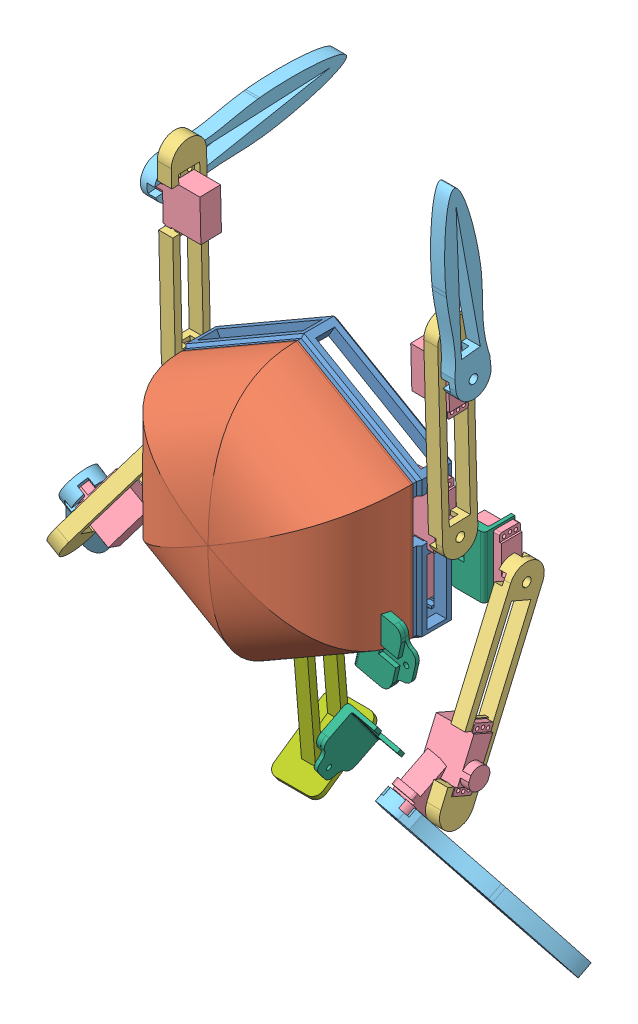
SolidWorks assembly robot, configuration Défaut. Lengths in mm.
Overall size (313.2 378.09 164.08).
31 component instances, 7 part files, 53 mates.
Components (placement in the parent):
- DAT PIECE-1: DAT PIECE [Défaut] at (-10.8836 70.1745 0) size (134 146.8 22)
- coque-1: coque [Défaut] at (-123.3481 -61.863 48.1765) x (0.5 0.866025 0) z (0 0 1) size (135.25 154.89 56.25)
- testBras-1: testBras [Défaut] at (78.5087 -93.5274 11.0123) x (0 -0.918186 0.39615) z (-1 0 0) size (120 20 26.15)
  - bras-1: bras [Défaut] at (-74.5383 -8.1052 -2) size (120 20 8)
  - servo-1: servo [Défaut] at (-8.5231 -3.9052 -3.5325) x (0 0 1) z (0 1 0) size (26.15 32.39 11.68)
- testBras-2: testBras [Défaut] at (-114.0009 -54.5505 25.2701) x (-0.418153 -0.72841 0.54274) z (0.867258 -0.49786 0) size (120 20 26.15)
  - bras-1: bras [Défaut] at (-74.5383 -8.1052 -2) size (120 20 8)
  - servo-1: servo [Défaut] at (-8.5231 -3.9052 -3.5325) x (0 0 1) z (0 1 0) size (26.15 32.39 11.68)
- pied-2: pied [Défaut] at (-131.5029 -60.6202 37.1735) x (-0.425802 -0.741735 -0.51819) z (0.867258 -0.49786 0) size (110.07 20 8)
- testBras-3: testBras [Défaut] at (-88.8405 91.642 9.4129) x (0 0.999727 0.023379) z (1 0 0) size (120 20 26.15)
  - bras-1: bras [Défaut] at (-74.5383 -8.1052 -2) size (120 20 8)
  - servo-1: servo [Défaut] at (-8.5231 -3.9052 -3.5325) x (0 0 1) z (0 1 0) size (26.15 32.39 11.68)
- testBras-4: testBras [Défaut] at (67.0733 79.8272 13.531) x (0 0.999613 0.027801) z (-1 0 0) size (120 20 26.15)
  - bras-1: bras [Défaut] at (-74.5383 -8.1052 -2) size (120 20 8)
  - servo-1: servo [Défaut] at (-8.5231 -3.9052 -3.5325) x (0 0 1) z (0 1 0) size (26.15 32.39 11.68)
- pied-4: pied [Défaut] at (78.8301 87.9868 21.7678) x (0 0.99396 0.109744) z (-1 0 0) size (110.07 20 8)
- servo-10: servo [Défaut] at (48.9164 -36.2368 -3.2325) x (0 0 1) z (-1 0 0) size (26.15 32.39 11.68)
- servo-11: servo [Défaut] at (-58.9996 -36.2368 -3.2325) x (0 0 1) z (-1 0 0) size (26.15 32.39 11.68)
- servo-12: servo [Défaut] at (60.6489 23.0996 3.7) x (-1 0 0) z (0 0 1) size (26.15 32.39 11.68)
- servo-13: servo [Défaut] at (-82.4161 -0.6494 3.7) size (26.15 32.39 11.68)
- servo-14: servo [Défaut] at (-7.6601 -44.5704 8.316) size (26.15 32.39 11.68)
- pantiltDD-1: pantiltDD [Défaut] at (53.2417 -26.5493 20.7075) x (0 0 1) z (0.97536 -0.220619 0) size (17.5 35 28.97)
- pantiltDD-2: pantiltDD [Défaut] at (-72.2366 -7.8234 20.7075) x (0 0 1) z (-0.867258 0.49786 0) size (17.5 35 28.97)
- pantiltDD-3: pantiltDD [Défaut] at (26.3946 -111.469 22.237) x (-0.97536 0.220619 0) z (-0.135924 -0.600921 0.787666) size (17.5 35 28.97)
- servo-15: servo [Défaut] at (-86.5996 -19.7221 -22.6409) x (0.867258 -0.49786 0) z (0 0 1) size (26.15 32.39 11.68)
- servo-16: servo [Défaut] at (72.0843 -6.6076 -22.6409) x (-1 0 0) z (0 0 1) size (26.15 32.39 11.68)
- pied-5: pied [Défaut] at (70.1824 -115.1027 46.0099) x (0.677703 -0.636329 -0.368516) z (0.135924 0.600921 -0.787666) size (110.07 20 8)
- servo-17: servo [Défaut] at (55.2998 -127.2042 23.5139) x (0.135924 0.600921 -0.787666) z (0.97536 -0.220619 0) size (26.15 32.39 11.68)
- pied-6: pied [Défaut] at (-100.7974 90.87 10.4039) x (0 0.118313 -0.992976) z (1 0 0) size (110.07 20 8)
- patteArriere-1: patteArriere [Défaut] at (-16.0845 -27.654 24.1475) x (0 -0.996691 -0.081285) z (1 0 0) size (135 38.82 28)
- pantiltDD-4: pantiltDD [Défaut] at (58.5518 -36.0076 -22.9569) x (0 0 1) z (-1 0 0) size (17.5 35 28.97)
Mates (geometry in assembly coordinates):
- Coaxiale7: concentric aligned: circle of testBras-2/servo-1; circle of pied-2
- Distance8: distance = 0.2 mm anti-aligned: plane of pied-2 through (-125.7142 -57.9683 28.6209) normal (0.867258 -0.49786 0); plane of testBras-2/servo-1 through (-125.5408 -58.0678 28.6209) normal (-0.867258 0.49786 0)
- Coaxiale9: concentric aligned: circle of ?; circle of testBras-4/bras-1
- Distance10: distance = 0.2 mm anti-aligned: plane of testBras-4/bras-1 through (74.1733 117.9458 9.5194) normal (-1 0 0); plane of ? through (74.3733 117.9458 9.5194) normal (1 0 0)
- Coaxiale11: concentric aligned: circle of testBras-4/servo-1; circle of pied-4
- Distance12: distance = 0.2 mm anti-aligned: plane of pied-4 through (75.1301 89.0842 11.8282) normal (-1 0 0); plane of testBras-4/servo-1 through (75.3301 89.0842 11.8282) normal (1 0 0)
- Distance17: distance = 0.2 mm anti-aligned: plane of servo-10 through (48.9164 -8.1698 1.3) normal (0 0 1); plane of DAT PIECE-1 through (19.1164 -41.8314 1.5) normal (0 0 -1)
- Coïncidente8: coincident anti-aligned: plane of DAT PIECE-1 through (56.1164 31.4921 20) normal (1 0 0); plane of servo-12 through (56.1164 -4.9674 3.7) normal (-1 0 0)
- Distance20: distance = 0.2 mm anti-aligned: plane of servo-12 through (60.6489 -0.6494 3.7) normal (0 0 -1); plane of DAT PIECE-1 through (56.1164 23.4506 3.5) normal (0 0 1)
- Distance21: distance = 0.4 mm anti-aligned: plane of servo-13 through (-82.4161 -0.6494 15.384) normal (0 -1 0); plane of DAT PIECE-1 through (56.1164 -1.0494 3.5) normal (0 1 0)
- Coïncidente11: coincident anti-aligned: plane of DAT PIECE-1 through (-77.8836 31.4921 20) normal (-1 0 0); plane of servo-13 through (-77.8836 27.4176 3.7) normal (1 0 0)
- Distance22: distance = 0.2 mm anti-aligned: plane of servo-13 through (-82.4161 23.0996 3.7) normal (0 0 -1); plane of DAT PIECE-1 through (56.1164 23.4506 3.5) normal (0 0 1)
- Distance23: distance = 0.4 mm anti-aligned: plane of servo-12 through (60.6489 -0.6494 15.384) normal (0 -1 0); plane of DAT PIECE-1 through (56.1164 -1.0494 3.5) normal (0 1 0)
- Coïncidente20: coincident: point of DAT PIECE-1; point of coque-1
- Coïncidente22: coincident anti-aligned: plane of DAT PIECE-1 through (54.6164 -45.0069 22) normal (0 0 1); plane of coque-1 through (-76.3836 30.626 22) normal (0 0 -1)
- Coïncidente23: coincident: plane of servo-11 through (-64.8642 -18.5076 -7.9569) normal (0 0 -1); plane of pantiltDD-2 through (-58.7534 -1.837 -7.9569) normal (0 0 1)
- Coaxiale13: concentric: circle of servo-11; circle of pantiltDD-2
- Coaxiale14: concentric: circle of servo-10; circle of pantiltDD-1
- Coïncidente24: coincident: plane of servo-10 through (43.0518 -18.5076 -7.9569) normal (0 0 -1); plane of pantiltDD-1 through (42.117 -36.2382 -7.9569) normal (0 0 1)
- Coïncidente25: coincident: plane of pantiltDD-2 through (-85.4695 -26.8574 -22.6409) normal (-0.867258 0.49786 0); plane of servo-15 through (-68.6953 2.3626 -22.6409) normal (0.867258 -0.49786 0)
- Coaxiale15: concentric: circle of pantiltDD-2; circle of servo-15
- Coïncidente27: coincident anti-aligned: plane of testBras-2/bras-1 through (-81.8702 -1.9943 -16.7763) normal (0.867258 -0.49786 0); plane of servo-15 through (-81.8702 -1.9943 -16.7763) normal (-0.867258 0.49786 0)
- Coaxiale16: concentric aligned: circle of testBras-2/bras-1; circle of servo-15
- Coaxiale17: concentric: circle of testBras-1/servo-1; circle of pantiltDD-3
- Coïncidente28: coincident: plane of testBras-1/servo-1; plane of pantiltDD-3 through (53.4684 -121.7028 8.0396) normal (-0.97536 0.220619 0)
- Coïncidente29: coincident: plane of pantiltDD-1 through (60.2877 -4.4641 -22.6409) normal (0.97536 -0.220619 0); plane of servo-16
- Coaxiale18: concentric: circle of pantiltDD-1; circle of servo-16
- Coïncidente30: coincident anti-aligned: plane of testBras-1/bras-1 through (76.8087 -24.3368 -16.7763) normal (-1 0 0); plane of servo-16 through (76.8087 -24.3368 -16.7763) normal (1 0 0)
- Coaxiale19: concentric aligned: circle of testBras-1/bras-1; circle of servo-16
- Coaxiale20: concentric: circle of pantiltDD-1; circle of servo-16
- Coaxiale21: concentric: circle of pantiltDD-2; circle of servo-15
- Coïncidente31: coincident: plane of pantiltDD-3 through (72.4165 -104.491 38.0415) normal (-0.135924 -0.600921 0.787666); plane of servo-17 through (60.7932 -102.9178 37.2359) normal (0.135924 0.600921 -0.787666)
- Coaxiale23: concentric: circle of pantiltDD-3; circle of servo-17
- Coaxiale24: concentric: circle of pantiltDD-3; circle of servo-17
- Coaxiale25: concentric aligned: circle of pied-5; circle of servo-17
- Coïncidente32: coincident anti-aligned: plane of pied-5 through (63.4586 -117.7164 38.1581) normal (0.135924 0.600921 -0.787666); plane of servo-17 through (63.4586 -117.7164 38.1581) normal (-0.135924 -0.600921 0.787666)
- Coaxiale26: concentric aligned: circle of testBras-3/servo-1; circle of pied-6
- Coïncidente33: coincident anti-aligned: plane of testBras-3/servo-1 through (-97.0974 100.7998 11.5871) normal (-1 0 0); plane of pied-6 through (-97.0974 100.7998 11.5871) normal (1 0 0)
- Coïncidente34: coincident anti-aligned: plane of testBras-3/bras-1 through (-87.1405 17.0798 9.5646) normal (1 0 0); plane of servo-13 through (-87.1405 17.0798 9.5646) normal (-1 0 0)
- Coaxiale27: concentric aligned: circle of testBras-3/bras-1; circle of servo-13
- Coaxiale28: concentric aligned: circle of testBras-4/bras-1; circle of servo-12
- Coïncidente35: coincident anti-aligned: plane of testBras-4/bras-1 through (65.3733 5.3704 9.5646) normal (-1 0 0); plane of servo-12 through (65.3733 5.3704 9.5646) normal (1 0 0)
- Coïncidente36: coincident anti-aligned: plane of DAT PIECE-1 through (54.6164 -45.0069 20) normal (0 0 -1); plane of servo-14 through (-7.6601 -20.8214 20) normal (0 0 1)
- Coïncidente37: coincident anti-aligned: plane of servo-14 through (-12.3845 -26.8412 14.1806) normal (-1 0 0); plane of patteArriere-1 through (-12.3845 -26.8412 14.1806) normal (1 0 0)
- Coaxiale29: concentric aligned: circle of servo-14; circle of patteArriere-1
- Coïncidente38: coincident anti-aligned: plane of DAT PIECE-1 through (-3.1277 -13.8214 -38.0317) normal (-1 0 0); plane of servo-14 through (-3.1277 -16.5034 8.316) normal (1 0 0)
- Distance24: distance = 0.2 mm anti-aligned: plane of servo-14 through (-7.6601 -44.5704 20) normal (0 -1 0); plane of DAT PIECE-1 through (13.7633 -44.7704 49.47) normal (0 1 0)
- Coaxiale33: concentric anti-aligned: circle of DAT PIECE-1; circle of servo-10
- Coaxiale34: concentric aligned: circle of DAT PIECE-1; circle of servo-10
- Coaxiale35: concentric anti-aligned: circle of servo-10; circle of pantiltDD-4
- Coïncidente39: coincident anti-aligned: plane of servo-10 through (43.0518 -18.5076 -7.9569) normal (0 0 -1); plane of pantiltDD-4 through (51.5775 -6.0076 -7.9569) normal (0 0 1)
- Coïncidente40: coincident anti-aligned: plane of servo-16 through (67.5518 -34.6746 -22.6409) normal (-1 0 0); plane of pantiltDD-4 through (67.5518 -36.0076 -7.9569) normal (1 0 0)
- Distance26: distance = 0.2 mm anti-aligned: plane of servo-16 through (72.0843 -6.6076 -10.9569) normal (0 1 0); plane of pantiltDD-4 through (67.5518 -6.4076 -11.5269) normal (0 -1 0)
